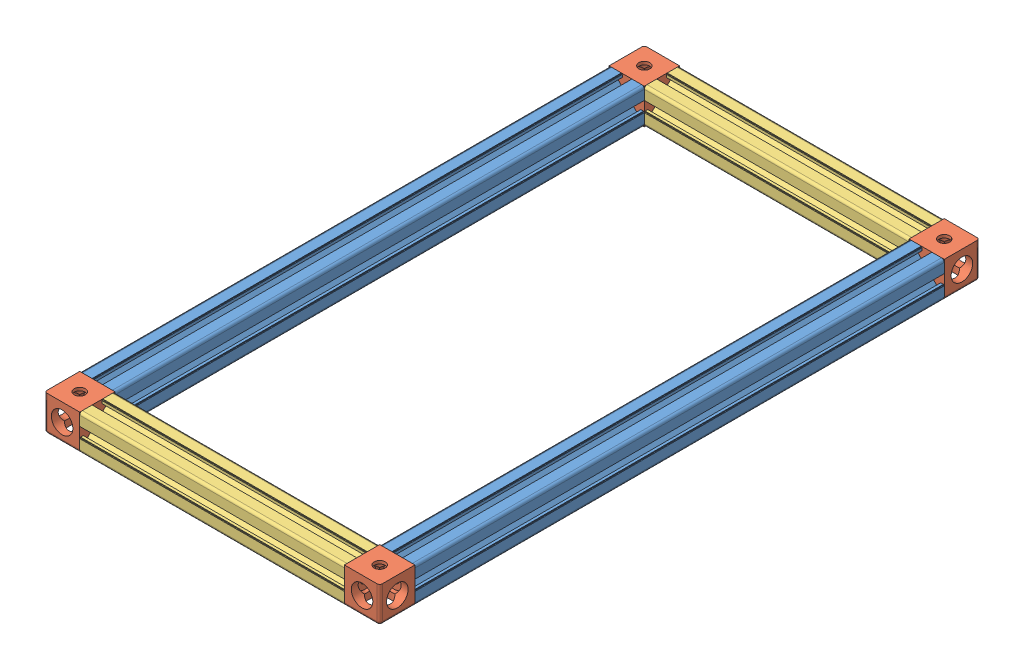
SolidWorks assembly cadre_600x300mm, configuration Défaut. Lengths in mm.
Overall size (380 40 680).
8 component instances, 3 part files, 30 mates.
Components (placement in the parent):
- prof_40x40x600mm-1: prof_40x40x600mm [Défaut] at (-14.8937 4.0689 600) size (40 40 600)
- Rexroth-Default-1: Rexroth-Default [Default] at (-14.8937 24.0689 720) x (0 -1 0) z (-1 0 0) size (40 40 40)
- prof_40x40x600mm-3: prof_40x40x600mm [Défaut] at (325.1063 4.0689 600) size (40 40 600)
- Rexroth-Default-3: Rexroth-Default [Default] at (-14.8937 24.0689 80) x (0 -1 0) z (0 0 -1) size (40 40 40)
- Rexroth-Default-4: Rexroth-Default [Default] at (325.1063 24.0689 80) x (0 -1 0) z (1 0 0) size (40 40 40)
- Rexroth-Default-5: Rexroth-Default [Default] at (325.1063 24.0689 720) x (0 -1 0) z (0 0 1) size (40 40 40)
- prof_40x40x300mm-1: prof_40x40x300mm [Défaut] at (105.1063 4.0689 720) x (0 0 1) z (-1 0 0) size (40 40 300)
- prof_40x40x300mm-2: prof_40x40x300mm [Défaut] at (105.1063 4.0689 80) x (0 0 1) z (-1 0 0) size (40 40 300)
Mates (geometry in assembly coordinates):
- Coïncidente1: coincident anti-aligned: plane of prof_40x40x600mm-1 through (2.1063 -12.9311 700) normal (0 0 1); plane of Rexroth-Default-1 through (-14.8937 4.0689 700) normal (0 0 -1)
- Coïncidente2: coincident aligned: plane of prof_40x40x600mm-1 through (-20.8937 24.0689 100) normal (0 1 0); plane of Rexroth-Default-1 through (-14.8937 24.0689 720) normal (0 1 0)
- Coïncidente3: coincident aligned: plane of prof_40x40x600mm-1 through (-34.8937 21.0689 100) normal (-1 0 0); plane of Rexroth-Default-1 through (-34.8937 4.0689 720) normal (-1 0 0)
- Coïncidente4: coincident anti-aligned: plane of Rexroth-Default-1 through (5.1063 4.0689 720) normal (1 0 0); plane of prof_40x40x300mm-1 through (5.1063 -12.9311 737) normal (-1 0 0)
- Coïncidente5: coincident aligned: plane of Rexroth-Default-1 through (-14.8937 4.0689 740) normal (0 0 1); plane of prof_40x40x300mm-1 through (605.1063 10.0689 740) normal (0 0 1)
- Coïncidente6: coincident aligned: plane of Rexroth-Default-1 through (-14.8937 24.0689 720) normal (0 1 0); plane of prof_40x40x300mm-1 through (605.1063 24.0689 737) normal (0 1 0)
- Coïncidente7: coincident anti-aligned: plane of prof_40x40x300mm-1 through (605.1063 -12.9311 737) normal (1 0 0); plane of Rexroth-Default-5 through (605.1063 4.0689 720) normal (-1 0 0)
- Coïncidente8: coincident aligned: plane of prof_40x40x300mm-1 through (605.1063 24.0689 714) normal (0 1 0); plane of Rexroth-Default-5 through (625.1063 24.0689 720) normal (0 1 0)
- Coïncidente9: coincident aligned: plane of prof_40x40x300mm-1 through (605.1063 -12.9311 740) normal (0 0 1); plane of Rexroth-Default-5 through (625.1063 4.0689 740) normal (0 0 1)
- Coïncidente10: coincident anti-aligned: plane of prof_40x40x600mm-3 through (342.1063 -12.9311 700) normal (0 0 1); plane of Rexroth-Default-5 through (325.1063 4.0689 700) normal (0 0 -1)
- Coïncidente11: coincident aligned: plane of prof_40x40x300mm-1 through (605.1063 24.0689 714) normal (0 1 0); plane of prof_40x40x600mm-3 through (642.1063 24.0689 100) normal (0 1 0)
- Coïncidente12: coincident aligned: plane of prof_40x40x600mm-3 through (345.1063 10.0689 100) normal (1 0 0); plane of Rexroth-Default-5 through (345.1063 4.0689 720) normal (1 0 0)
- Coïncidente13: coincident anti-aligned: plane of prof_40x40x600mm-1 through (2.1063 -12.9311 100) normal (0 0 -1); plane of Rexroth-Default-3 through (-14.8937 4.0689 100) normal (0 0 1)
- Coïncidente14: coincident aligned: plane of prof_40x40x600mm-1 through (-20.8937 24.0689 100) normal (0 1 0); plane of Rexroth-Default-3 through (-14.8937 24.0689 80) normal (0 1 0)
- Coïncidente15: coincident aligned: plane of prof_40x40x600mm-1 through (5.1063 10.0689 100) normal (1 0 0); plane of Rexroth-Default-3 through (5.1063 4.0689 80) normal (1 0 0)
- Coïncidente16: coincident anti-aligned: plane of prof_40x40x600mm-3 through (342.1063 -12.9311 100) normal (0 0 -1); plane of Rexroth-Default-4 through (325.1063 4.0689 100) normal (0 0 1)
- Coïncidente17: coincident aligned: plane of prof_40x40x600mm-3 through (345.1063 10.0689 100) normal (1 0 0); plane of Rexroth-Default-4 through (345.1063 4.0689 80) normal (1 0 0)
- Coïncidente18: coincident aligned: plane of prof_40x40x600mm-3 through (342.1063 24.0689 100) normal (0 1 0); plane of Rexroth-Default-4 through (325.1063 24.0689 80) normal (0 1 0)
- Coïncidente19: coincident anti-aligned: plane of ? through (5.1063 -12.9311 63) normal (-1 0 0); plane of Rexroth-Default-3 through (5.1063 4.0689 80) normal (1 0 0)
- Coïncidente20: coincident aligned: plane of ? through (5.1063 10.0689 60) normal (0 0 -1); plane of Rexroth-Default-3 through (-14.8937 4.0689 60) normal (0 0 -1)
- Coïncidente21: coincident aligned: plane of ? through (5.1063 24.0689 63) normal (0 1 0); plane of Rexroth-Default-3 through (-14.8937 24.0689 80) normal (0 1 0)
- Coïncidente22: coincident anti-aligned: plane of Rexroth-Default-1 through (5.1063 4.0689 720) normal (1 0 0); plane of prof_40x40x300mm-1 through (5.1063 -12.9311 737) normal (-1 0 0)
- Coïncidente23: coincident aligned: plane of Rexroth-Default-1 through (-14.8937 24.0689 720) normal (0 1 0); plane of prof_40x40x300mm-1 through (305.1063 24.0689 714) normal (0 1 0)
- Coïncidente24: coincident aligned: plane of Rexroth-Default-1 through (-14.8937 4.0689 740) normal (0 0 1); plane of prof_40x40x300mm-1 through (305.1063 10.0689 740) normal (0 0 1)
- Coïncidente25: coincident anti-aligned: plane of Rexroth-Default-5 through (305.1063 4.0689 720) normal (-1 0 0); plane of prof_40x40x300mm-1 through (305.1063 -12.9311 737) normal (1 0 0)
- Coïncidente26: coincident aligned: plane of Rexroth-Default-5 through (325.1063 24.0689 720) normal (0 1 0); plane of prof_40x40x300mm-1 through (305.1063 24.0689 714) normal (0 1 0)
- Coïncidente27: coincident aligned: plane of Rexroth-Default-5 through (325.1063 4.0689 740) normal (0 0 1); plane of prof_40x40x300mm-1 through (305.1063 10.0689 740) normal (0 0 1)
- Coïncidente28: coincident anti-aligned: plane of Rexroth-Default-3 through (5.1063 4.0689 80) normal (1 0 0); plane of prof_40x40x300mm-2 through (5.1063 -12.9311 97) normal (-1 0 0)
- Coïncidente29: coincident aligned: plane of Rexroth-Default-3 through (-14.8937 24.0689 80) normal (0 1 0); plane of prof_40x40x300mm-2 through (305.1063 24.0689 74) normal (0 1 0)
- Coïncidente30: coincident aligned: plane of Rexroth-Default-3 through (-14.8937 4.0689 60) normal (0 0 -1); plane of prof_40x40x300mm-2 through (305.1063 21.0689 60) normal (0 0 -1)
